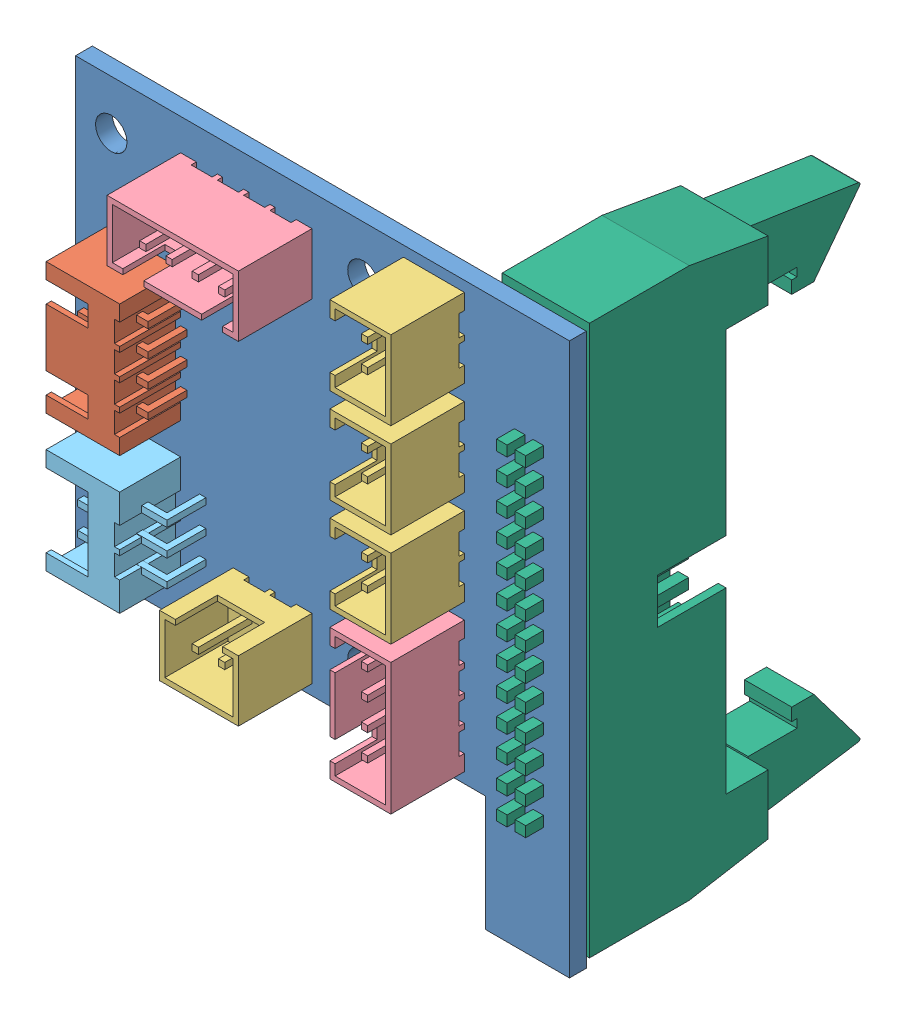
SolidWorks assembly X40喷头电路板装配, configuration 默认. Lengths in mm.
Overall size (47.3 53.3 36.24).
10 component instances, 6 part files, 26 mates.
Components (placement in the parent):
- 26P喷头电路板-1: 26P喷头电路板 [默认] at (-21.0199 -0.1523 -0.8) size (47 52.5 1.6)
- XH2.54弯座4p-1: XH2.54弯座4p [默认] at (-34.5199 1.0377 0.8) x (0 1 0) z (0 0 1) size (12.5 7.6 9.2)
- XH2.54直座2p-2: XH2.54直座2p [默认] at (-7.5199 25.0977 0.8) x (0 -1 0) z (-1 0 0) size (7.5 9.4 5.8)
- XH2.54直座4p-1: XH2.54直座4p [默认] at (-7.5199 -1.9023 0.8) x (0 -1 0) z (-1 0 0) size (12.5 9 5.8)
- XH2.54弯座3p-1: XH2.54弯座3p [默认] at (-34.5199 -11.9623 0.8) x (0 1 0) z (0 0 1) size (10 9.4 8.7)
- 26P牛角座直针-1: 26P牛角座直针 [默认] at (-5.5199 0.7477 -0.8) x (0 -1 0) z (1 0 0) size (52.3 30.94 8.3)
- XH2.54直座2p-3: XH2.54直座2p [默认] at (-7.5199 16.0977 0.8) x (0 -1 0) z (-1 0 0) size (7.5 9.4 5.8)
- XH2.54直座2p-4: XH2.54直座2p [默认] at (-7.5199 7.0977 0.8) x (0 -1 0) z (-1 0 0) size (7.5 9.4 5.8)
- XH2.54直座2p-5: XH2.54直座2p [默认] at (-22.0199 -14.4023 0.8) x (-1 0 0) z (0 1 0) size (7.5 9.4 5.8)
- XH2.54直座4p-2: XH2.54直座4p [默认] at (-34.5199 23.0977 0.8) x (1 0 0) z (0 -1 0) size (12.5 9 5.8)
Mates (geometry in assembly coordinates):
- 重合3: coincident anti-aligned: plane of 26P喷头电路板-1 through (-21.0199 -0.1523 0.8) normal (0 0 1); plane of XH2.54弯座4p-1 through (-34.5199 1.0377 0.8) normal (0 0 -1)
- 重合5: coincident anti-aligned: plane of 26P喷头电路板-1 through (-21.0199 -0.1523 0.8) normal (0 0 1); plane of ? through (-13.8199 13.5977 0.8) normal (0 0 -1)
- 重合7: coincident anti-aligned: plane of 26P喷头电路板-1 through (-21.0199 -0.1523 0.8) normal (0 0 1); plane of XH2.54直座2p-2 through (-13.3199 25.0977 0.8) normal (0 0 -1)
- 重合9: coincident anti-aligned: plane of 26P喷头电路板-1 through (-21.0199 -0.1523 0.8) normal (0 0 1); plane of XH2.54直座4p-1 through (-13.3199 -1.9023 0.8) normal (0 0 -1)
- 重合10: coincident aligned: plane of ? through (-8.0199 13.5977 0.8) normal (1 0 0); plane of XH2.54直座4p-1 through (-8.0199 2.0977 0.8) normal (1 0 0)
- 重合11: coincident aligned: plane of ? through (-8.0199 13.5977 0.8) normal (1 0 0); plane of XH2.54直座2p-2 through (-8.0199 25.0977 0.8) normal (1 0 0)
- 距离6: distance = 1 mm aligned: plane of 26P喷头电路板-1 through (-44.5199 26.0977 0.8) normal (0 1 0); plane of XH2.54直座2p-2 through (-13.3199 25.0977 0.8) normal (0 1 0)
- 距离4: distance = 4 mm anti-aligned: plane of XH2.54直座2p-2 through (-13.8199 17.5977 0.8) normal (0 -1 0); plane of ? through (-13.8199 13.5977 0.8) normal (0 1 0)
- 距离7: distance = 4 mm anti-aligned: plane of ? through (-13.8199 6.0977 0.8) normal (0 -1 0); plane of XH2.54直座4p-1 through (-13.8199 2.0977 0.8) normal (0 1 0)
- 重合16: coincident anti-aligned: plane of 26P喷头电路板-1 through (-21.0199 -0.1523 -0.8) normal (0 0 -1); plane of 26P牛角座直针-1 through (2.7801 26.8977 -0.8) normal (0 0 1)
- 距离11: distance = 39 mm aligned: plane of 26P牛角座直针-1 through (-5.5199 0.7477 -0.8) normal (-1 0 0); plane of 26P喷头电路板-1 through (-44.5199 26.0977 0.8) normal (-1 0 0)
- 距离12: distance = 0.8 mm aligned: plane of 26P喷头电路板-1 through (-44.5199 26.0977 0.8) normal (0 1 0); plane of 26P牛角座直针-1 through (2.7801 26.8977 -10.3) normal (0 1 0)
- 重合22: coincident anti-aligned: plane of 26P喷头电路板-1 through (-21.0199 -0.1523 0.8) normal (0 0 1); plane of XH2.54弯座3p-1 through (-34.5199 -11.9623 0.8) normal (0 0 -1)
- 距离14: distance = 5.6 mm aligned: plane of XH2.54弯座3p-1 through (-32.1199 -9.8023 4.5) normal (0 -1 0); plane of 26P喷头电路板-1 through (-5.5199 -15.4023 0.8) normal (0 -1 0)
- 距离17: distance = 10 mm aligned: plane of XH2.54直座2p-2 through (-7.5199 25.0977 0.8) normal (1 0 0); plane of 26P喷头电路板-1 through (2.4801 26.0977 0.8) normal (1 0 0)
- 重合24: coincident aligned: plane of XH2.54直座4p-1 through (-7.5199 -1.9023 0.8) normal (1 0 0); plane of XH2.54直座2p-4 through (-7.5199 7.0977 0.8) normal (1 0 0)
- 距离18: distance = 28 mm aligned: plane of XH2.54直座4p-1 through (-13.3199 -1.9023 0.8) normal (0 1 0); plane of 26P喷头电路板-1 through (-44.5199 26.0977 0.8) normal (0 1 0)
- 重合26: coincident aligned: plane of XH2.54弯座4p-1 through (-41.5199 1.0377 6.6) normal (-1 0 0); plane of XH2.54弯座3p-1 through (-41.5199 -11.9623 6.6) normal (-1 0 0)
- 距离19: distance = 3 mm anti-aligned: plane of XH2.54弯座4p-1 through (-34.5199 1.0377 6.6) normal (0 -1 0); plane of XH2.54弯座3p-1 through (-34.5199 -1.9623 6.6) normal (0 1 0)
- 距离20: distance = 3 mm aligned: plane of XH2.54弯座3p-1 through (-41.5199 -11.9623 6.6) normal (-1 0 0); plane of 26P喷头电路板-1 through (-44.5199 26.0977 0.8) normal (-1 0 0)
- 重合30: coincident: plane of 26P喷头电路板-1 through (-21.0199 -0.1523 0.8) normal (0 0 1); plane of XH2.54直座2p-5 through (-21.0332 -8.6023 0.8) normal (0 0 -1)
- 重合31: coincident: plane of 26P喷头电路板-1 through (-21.0199 -0.1523 0.8) normal (0 0 1); plane of XH2.54直座4p-2 through (-19.4494 17.2977 0.8) normal (0 0 -1)
- 距离21: distance = 1 mm: plane of XH2.54直座2p-5 through (-22.0199 -14.4023 0.8) normal (0 -1 0); plane of 26P喷头电路板-1 through (-5.5199 -15.4023 0.8) normal (0 -1 0)
- 距离22: distance = 15 mm aligned: plane of XH2.54直座2p-5 through (-29.5199 -8.6023 0.8) normal (-1 0 0); plane of 26P喷头电路板-1 through (-44.5199 26.0977 0.8) normal (-1 0 0)
- 距离23: distance = 3 mm: plane of XH2.54直座4p-2 through (-34.5199 23.0977 0.8) normal (0 1 0); plane of 26P喷头电路板-1 through (-44.5199 26.0977 0.8) normal (0 1 0)
- 距离24: distance = 10 mm aligned: plane of XH2.54直座4p-2 through (-34.5199 17.2977 0.8) normal (-1 0 0); plane of 26P喷头电路板-1 through (-44.5199 26.0977 0.8) normal (-1 0 0)
